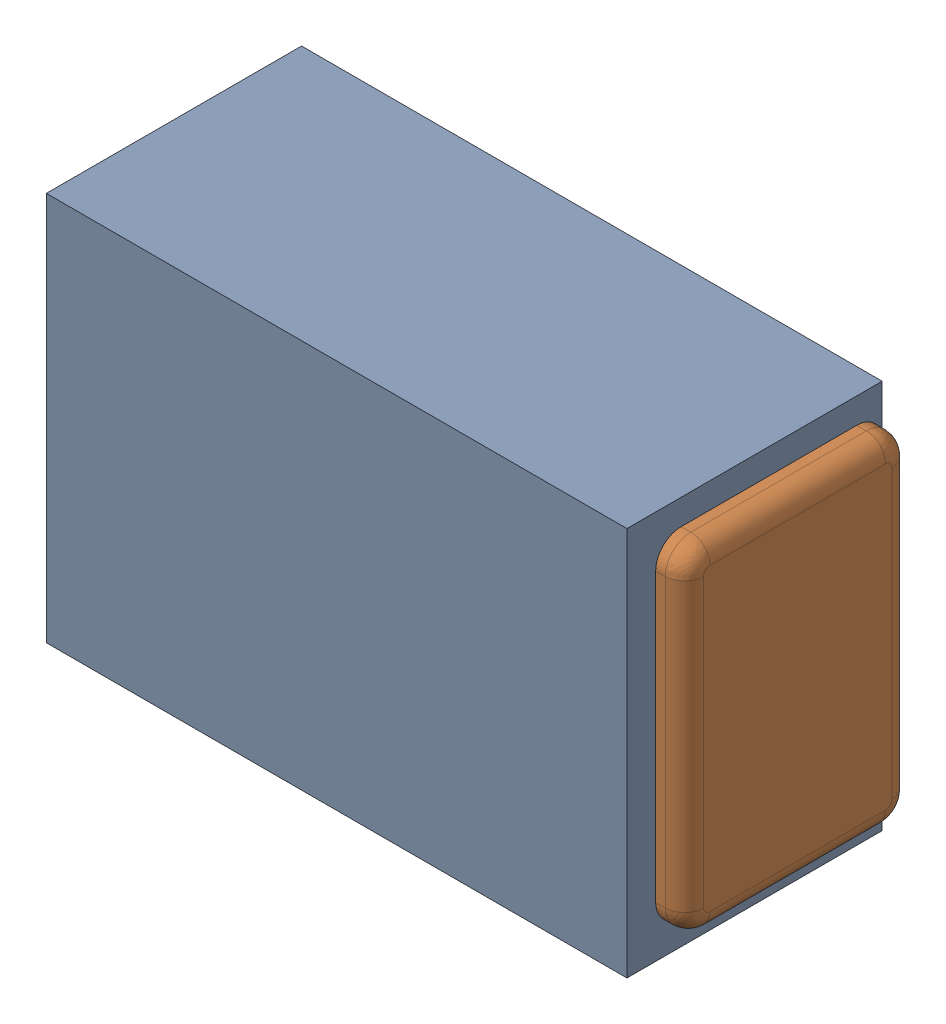
SolidWorks assembly C22, configuration Default. Lengths in mm.
Overall size (1 0.61 0.4).
3 component instances, 2 part files, 0 mates.
Components (placement in the parent):
- 1088880352-1: 1088880352 [Default] at (4.475 4.175 0) size (0.91 0.61 0.4)
  - Extruded-28-1: Extruded-28 [Default] at origin size (0.91 0.61 0.4)
- C0402-1: C0402 [Default] at (4.4751 4.1751 0) x (1 0 0) z (0 -1 0) size (1 0.36 0.54)
